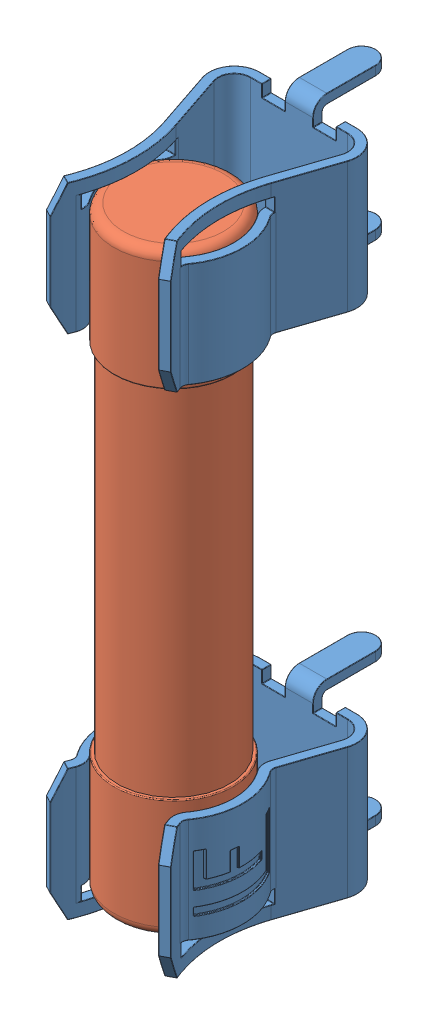
SolidWorks assembly User Library-Clips LF-102071 with fuse 6.3x32, configuration Default. Lengths in mm.
Overall size (7.9 35.2 14.61).
3 component instances, 2 part files, 0 mates.
Components (placement in the parent):
- User Library-Clips LF-102071 with fuse 6.3x32_LF 102071-1: User Library-Clips LF-102071 with fuse 6.3x32_LF 102071 [Default] at (0 -13.55 0) x (-1 0 0) z (0 1 0) size (7.9 14.61 8.1)
- User Library-Clips LF-102071 with fuse 6.3x32_LF 102071-2: User Library-Clips LF-102071 with fuse 6.3x32_LF 102071 [Default] at (0 13.55 0) x (1 0 0) z (0 -1 0) size (7.9 14.61 8.1)
- User Library-Clips LF-102071 with fuse 6.3x32_6,3x32-1: User Library-Clips LF-102071 with fuse 6.3x32_6,3x32 [Default] at (0 0 7.2) x (-1 0 0) z (0 -1 0) size (6.35 6.35 31.81)
